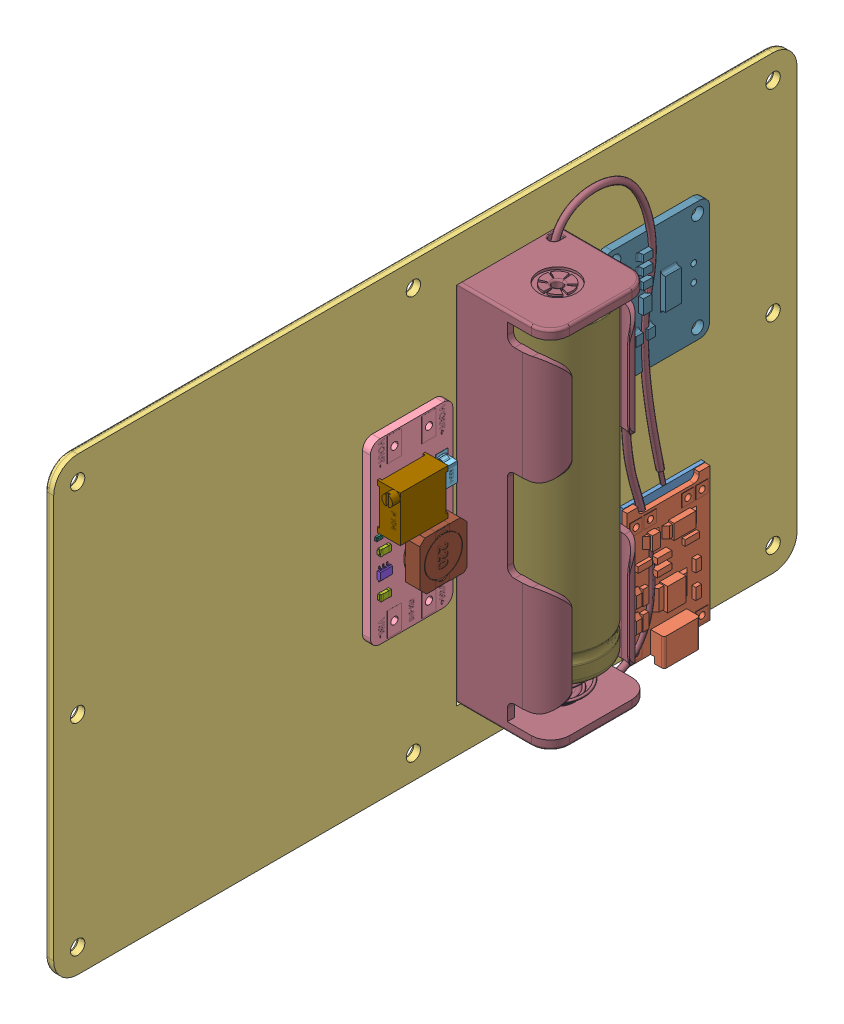
SolidWorks assembly Assem3, configuration Default. Lengths in mm.
Overall size (49.29 95.5 155).
19 component instances, 14 part files, 12 mates.
Components (placement in the parent):
- Part12-1: Part12 [Default] at (-50.5479 130.2142 -75.0436) x (0 1 0) z (1 0 0) size (26 17 0.8)
- tp4056 micro usb 18650 charger-1: tp4056 micro usb 18650 charger [Výchozí] at (-48.5479 142.2642 -83.2628) x (0 0 -1) z (1 0 0) size (17.3 29.2 4)
- Part2-1: Part2 [Default] at (-52.5479 175.2142 -32.0436) x (0 0 -1) z (1 0 0) size (155 94 2)
- MT3608 Converter.STEP-1: MT3608 Converter.STEP [Default] at (-50.5479 176.5567 -30.0329) x (0 -1 0) z (0 0 1) size (37.15 7.3 17.43)
  - MT3608 Converter PCB.STEP-1: MT3608 Converter PCB.STEP [Default] at origin size (37.15 1.67 17.2)
  - smdS537diode.STEP-1: smdS537diode.STEP [Default] at (-6.6188 1.7 -6.2378) size (6.5 2.06 2.5)
  - tinySMDResistor222.STEP-1: tinySMDResistor222.STEP [Default] at (-1.0169 1.5323 6.9503) x (0.008727 0 -0.999962) z (0.999962 0 0.008727) size (1.52 0.38 0.79)
  - smdceramiccapacitorbrown.STEP-1: smdceramiccapacitorbrown.STEP [Default] at (1.6628 1.65 5.9475) x (0.008727 0 -0.999962) z (0.999962 0 0.008727) size (2.52 0.61 1.3)
  - tinysmdChip6pin.STEP-1: tinysmdChip6pin.STEP [Default] at (5.7797 2.0883 4.6814) size (2.85 0.65 2.5)
  - smdceramiccapacitorbrown.STEP-2: smdceramiccapacitorbrown.STEP [Default] at (9.8138 1.65 5.9026) x (0.008727 0 -0.999962) z (0.999962 0 0.008727) size (2.52 0.61 1.3)
  - HorizonatalTrimmerP104.STEP-1: HorizonatalTrimmerP104.STEP [Default] at (-6.6754 6.45 2.4252) x (1 0 0) z (0 -1 0) size (9.5 11.65 7.3)
  - solder.STEP-1: solder.STEP [Default] at (-4.1552 0 3.4301) x (-0.837169 0 -0.546944) z (-0.546944 0 0.837169) size (1.17 0.65 1.17)
  - solder.STEP-2: solder.STEP [Default] at (-9.184 0 3.4301) x (-0.837169 0 -0.546944) z (-0.546944 0 0.837169) size (1.17 0.65 1.17)
  - solder.STEP-3: solder.STEP [Default] at (-6.6776 0 5.4144) x (-0.837169 0 -0.546944) z (-0.546944 0 0.837169) size (1.17 0.65 1.17)
  - smbInductor220.STEP-1: smbInductor220.STEP [Default] at (5.6448 2.15 -2.551) size (10.9 3.5 9.85)
- Assem battery-3: Assem battery [Default] at (-90.1453 256.3343 -18.0361) x (-0.383049 0 -0.923728) z (0 -1 0) size (45.9 34.33 92.22)
  - 18650-1: 18650 [Default] at (12.4817 58.8685 44.9948) x (0 0 1) z (-1 0 0) size (65 18.4 18.4)
  - 18650 Battery Holder.step-3: 18650 Battery Holder.step [Default] at (12.8648 57.9447 81.1202) x (-0.923728 -0.383049 0) z (0 0 -1) size (41.39 20 92.22)
- CJMCU-219 INA219.step-1: CJMCU-219 INA219.step [Default] at (-50.5479 204.7104 -69.9991) x (0 -1 0) z (0 0 1) size (25 2.5 22.3)
Mates (geometry in assembly coordinates):
- Coincident4: coincident anti-aligned: plane of Part12-1 through (-50.5479 130.2142 -75.0436) normal (-1 0 0); plane of Part2-1 through (-50.5479 217.2142 -107.0436) normal (1 0 0)
- Coincident19: coincident anti-aligned: plane of Part2-1 through (-50.5479 217.2142 -107.0436) normal (1 0 0); plane of MT3608 Converter.STEP-1/MT3608 Converter PCB.STEP-1 through (-50.5479 176.5567 -30.0329) normal (-1 0 0)
- Lock3: lock: unknown of Part2-1; unknown of MT3608 Converter.STEP-1/MT3608 Converter PCB.STEP-1
- Coincident24: coincident anti-aligned: line of Part12-1 through (-50.5479 156.2142 -75.0436) axis (0 -1 0); line of Part2-1 through (-50.5479 128.2142 -75.0436) axis (0 1 0)
- Lock4: lock: unknown of Part12-1; unknown of tp4056 micro usb 18650 charger-1
- Lock5: lock: unknown of Part12-1; unknown of tp4056 micro usb 18650 charger-1
- Lock6: lock: unknown of Part12-1; unknown of Part2-1
- Coincident29: coincident anti-aligned: plane of Assem battery-3/18650 Battery Holder.step-3 through (-51.5479 213.2142 -62.6153) normal (-1 0 0); plane of Part2-1 through (-51.5479 175.2142 -32.0436) normal (1 0 0)
- Coincident30: coincident anti-aligned: plane of Part2-1 through (-51.5479 213.2142 -32.0436) normal (0 -1 0); plane of Assem battery-3/18650 Battery Holder.step-3 through (-35.5479 213.2142 -58.6153) normal (0 1 0)
- Coincident31: coincident anti-aligned: plane of Part2-1 through (-51.5479 137.2142 -32.0436) normal (0 1 0); plane of Assem battery-3/18650 Battery Holder.step-3 through (-35.5479 137.2142 -58.6153) normal (0 -1 0)
- Coincident32: coincident anti-aligned: plane of Part2-1 through (-50.5479 217.2142 -107.0436) normal (1 0 0); plane of CJMCU-219 INA219.step-1 through (-50.5479 192.2104 -81.1491) normal (-1 0 0)
- Lock7: lock: unknown of Part2-1; unknown of CJMCU-219 INA219.step-1
